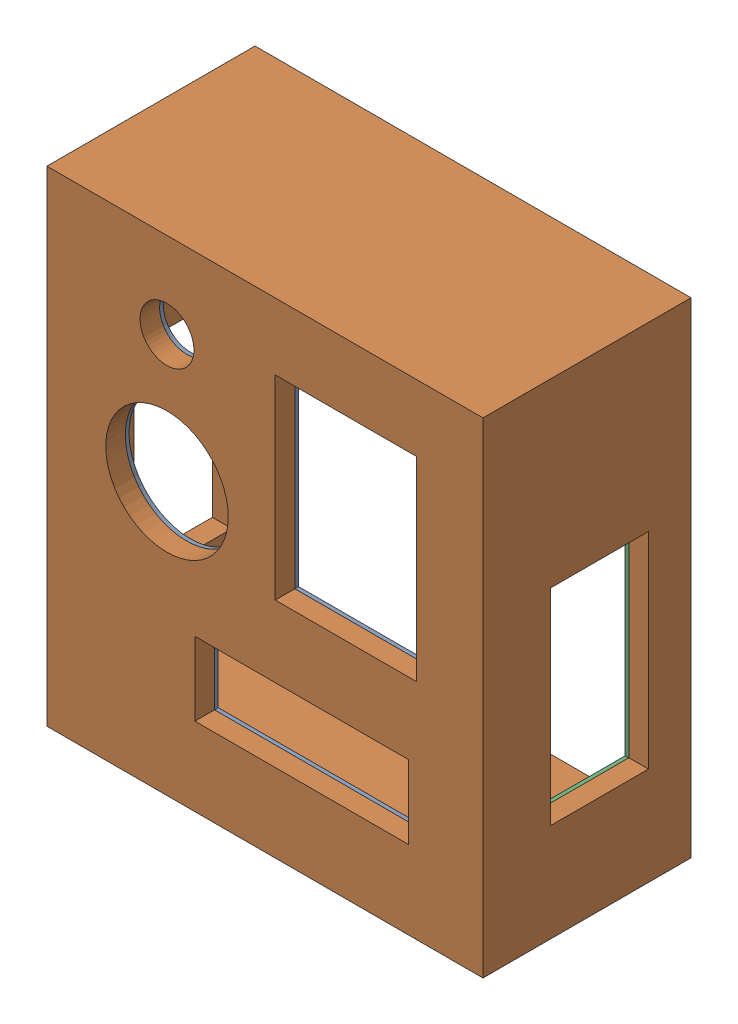
SolidWorks assembly Assembly for PLA, configuration Default. Lengths in mm.
Overall size (141.29 157.16 71.06).
3 component instances, 3 part files, 6 mates.
Components (placement in the parent):
- Front Panel-1: Front Panel [Default] at (135.0167 38.9889 207.3654) size (128.59 144.46 1.21)
- Front Side PLA Brayden-1: Front Side PLA Brayden [Default] at (135.0167 38.9889 208.5795) size (141.29 157.16 67.42)
- Right Panel-1: Right Panel [Default] at (198.0963 38.9889 175.6154) size (1.21 144.46 63.5)
Mates (geometry in assembly coordinates):
- Coincident1: coincident anti-aligned: plane of Front Panel-1 through (135.0167 38.9889 208.5795) normal (0 0 1); plane of Front Side PLA-1 through (135.0167 38.9889 208.5795) normal (0 0 -1)
- Coincident2: coincident aligned: line of Front Panel-1 through (70.723 -33.2424 208.5795) axis (0 1 0); line of Front Side PLA-1 through (70.723 -33.2424 208.5795) axis (0 1 0)
- Coincident3: coincident aligned: line of Front Panel-1 through (70.723 111.2201 208.5795) axis (1 0 0); line of Front Side PLA-1 through (70.723 111.2201 208.5795) axis (1 0 0)
- Coincident4: coincident anti-aligned: plane of Front Side PLA-1 through (199.3105 -33.2424 147.5078) normal (-1 0 0); plane of Right Panel-1 through (199.3105 38.9889 175.6154) normal (1 0 0)
- Coincident5: coincident aligned: line of Front Panel-1 through (199.3105 -33.2424 207.3654) axis (0 1 0); line of Right Panel-1 through (199.3105 -33.2424 207.3654) axis (0 1 0)
- Coincident6: coincident anti-aligned: line of Front Side PLA-1 through (199.3105 111.2201 147.5078) axis (0 0 1); line of Right Panel-1 through (199.3105 111.2201 207.3654) axis (0 0 -1)
